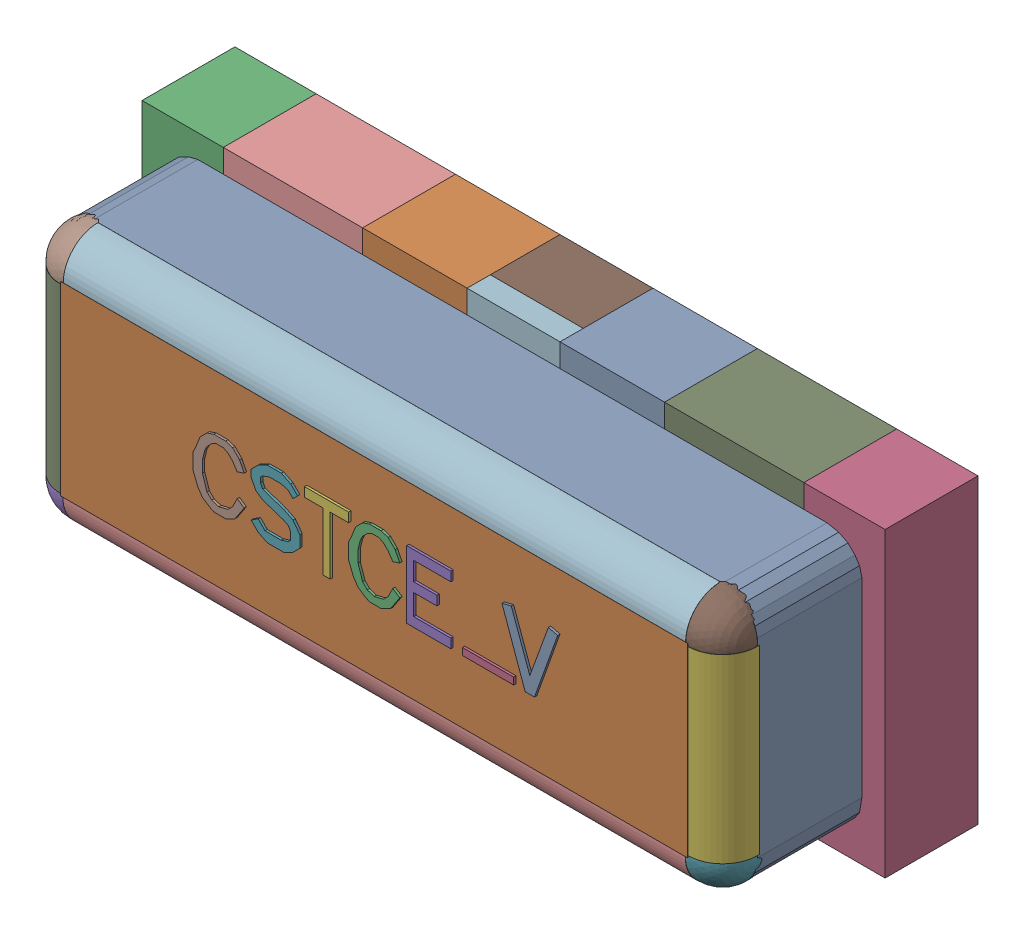
SolidWorks assembly User Library-Arduino Nano 3.0_User Library-CSTCE_V-1_Free-Models1, configuration Default. Lengths in mm.
Overall size (3.2 1.3 1.01).
50 component instances, 16 part files, 0 mates.
Components (placement in the parent):
- User Library-Arduino Nano 3.0_User Library-CSTCE_V-1_453563857-1: User Library-Arduino Nano 3.0_User Library-CSTCE_V-1_453563857 [Default] at (1.63 0.025 1.0127) size (0.24 0.29 0.01)
  - User Library-Arduino Nano 3.0_User Library-CSTCE_V-1_Extruded20-1: User Library-Arduino Nano 3.0_User Library-CSTCE_V-1_Extruded20 [Default] at origin size (0.24 0.29 0.01)
- User Library-Arduino Nano 3.0_User Library-CSTCE_V-1_453557585-1: User Library-Arduino Nano 3.0_User Library-CSTCE_V-1_453557585 [Default] at (0.95 0 0.8627) size (2.7 0.8 0.15)
  - User Library-Arduino Nano 3.0_User Library-CSTCE_V-1_Extruded15-1: User Library-Arduino Nano 3.0_User Library-CSTCE_V-1_Extruded15 [Default] at origin size (2.7 0.8 0.15)
- User Library-Arduino Nano 3.0_User Library-CSTCE_V-1_453563985-1: User Library-Arduino Nano 3.0_User Library-CSTCE_V-1_453563985 [Default] at (0.96 0.025 1.0127) size (0.22 0.29 0.01)
  - User Library-Arduino Nano 3.0_User Library-CSTCE_V-1_Extruded14-1: User Library-Arduino Nano 3.0_User Library-CSTCE_V-1_Extruded14 [Default] at origin size (0.22 0.29 0.01)
- User Library-Arduino Nano 3.0_User Library-CSTCE_V-1_453563601-1: User Library-Arduino Nano 3.0_User Library-CSTCE_V-1_453563601 [Default] at (1.45 -0.105 1.0127) size (0.22 0.03 0.01)
  - User Library-Arduino Nano 3.0_User Library-CSTCE_V-1_Extruded17-1: User Library-Arduino Nano 3.0_User Library-CSTCE_V-1_Extruded17 [Default] at origin size (0.22 0.03 0.01)
- User Library-Arduino Nano 3.0_User Library-CSTCE_V-1_453565905-1: User Library-Arduino Nano 3.0_User Library-CSTCE_V-1_453565905 [Default] at (1.195 0.025 1.0127) size (0.19 0.29 0.01)
  - User Library-Arduino Nano 3.0_User Library-CSTCE_V-1_Extruded21-1: User Library-Arduino Nano 3.0_User Library-CSTCE_V-1_Extruded21 [Default] at origin size (0.19 0.29 0.01)
- User Library-Arduino Nano 3.0_User Library-CSTCE_V-1_453566801-1: User Library-Arduino Nano 3.0_User Library-CSTCE_V-1_453566801 [Default] at (0.755 0.025 1.0127) size (0.19 0.29 0.01)
  - User Library-Arduino Nano 3.0_User Library-CSTCE_V-1_Extruded25-1: User Library-Arduino Nano 3.0_User Library-CSTCE_V-1_Extruded25 [Default] at origin size (0.19 0.29 0.01)
- User Library-Arduino Nano 3.0_User Library-CSTCE_V-1_453567057-1: User Library-Arduino Nano 3.0_User Library-CSTCE_V-1_453567057 [Default] at (0.535 0.025 1.0127) size (0.21 0.29 0.01)
  - User Library-Arduino Nano 3.0_User Library-CSTCE_V-1_Extruded23-1: User Library-Arduino Nano 3.0_User Library-CSTCE_V-1_Extruded23 [Default] at origin size (0.21 0.29 0.01)
- User Library-Arduino Nano 3.0_User Library-CSTCE_V-1_453563985-2: User Library-Arduino Nano 3.0_User Library-CSTCE_V-1_453563985 [Default] at (0.29 0.025 1.0127) size (0.22 0.29 0.01)
  - User Library-Arduino Nano 3.0_User Library-CSTCE_V-1_Extruded14-1: User Library-Arduino Nano 3.0_User Library-CSTCE_V-1_Extruded14 [Default] at origin size (0.22 0.29 0.01)
- User Library-Arduino Nano 3.0_User Library-CSTCE_V-1_453562833-1: User Library-Arduino Nano 3.0_User Library-CSTCE_V-1_453562833 [Default] at (1.9 0 0.0127) size (0.6 1.3 0.4)
  - User Library-Arduino Nano 3.0_User Library-CSTCE_V-1_Extruded18-1: User Library-Arduino Nano 3.0_User Library-CSTCE_V-1_Extruded18 [Default] at origin size (0.6 1.3 0.4)
- User Library-Arduino Nano 3.0_User Library-CSTCE_V-1_453562833-2: User Library-Arduino Nano 3.0_User Library-CSTCE_V-1_453562833 [Default] at (0 0 0.0127) size (0.6 1.3 0.4)
  - User Library-Arduino Nano 3.0_User Library-CSTCE_V-1_Extruded18-1: User Library-Arduino Nano 3.0_User Library-CSTCE_V-1_Extruded18 [Default] at origin size (0.6 1.3 0.4)
- User Library-Arduino Nano 3.0_User Library-CSTCE_V-1_453562065-1: User Library-Arduino Nano 3.0_User Library-CSTCE_V-1_453562065 [Default] at (0.95 0 0.0127) size (0.4 1.3 0.3)
  - User Library-Arduino Nano 3.0_User Library-CSTCE_V-1_Extruded16-1: User Library-Arduino Nano 3.0_User Library-CSTCE_V-1_Extruded16 [Default] at origin size (0.4 1.3 0.3)
- User Library-Arduino Nano 3.0_User Library-CSTCE_V-1_453566289-1: User Library-Arduino Nano 3.0_User Library-CSTCE_V-1_453566289 [Default] at (0.95 0 0.3127) size (0.4 1.3 0.1)
  - User Library-Arduino Nano 3.0_User Library-CSTCE_V-1_Extruded13-1: User Library-Arduino Nano 3.0_User Library-CSTCE_V-1_Extruded13 [Default] at origin size (0.4 1.3 0.1)
- User Library-Arduino Nano 3.0_User Library-CSTCE_V-1_453565777-1: User Library-Arduino Nano 3.0_User Library-CSTCE_V-1_453565777 [Default] at (1.375 0 0.0127) size (0.45 1.3 0.4)
  - User Library-Arduino Nano 3.0_User Library-CSTCE_V-1_Extruded24-1: User Library-Arduino Nano 3.0_User Library-CSTCE_V-1_Extruded24 [Default] at origin size (0.45 1.3 0.4)
- User Library-Arduino Nano 3.0_User Library-CSTCE_V-1_453565777-2: User Library-Arduino Nano 3.0_User Library-CSTCE_V-1_453565777 [Default] at (0.525 0 0.0127) size (0.45 1.3 0.4)
  - User Library-Arduino Nano 3.0_User Library-CSTCE_V-1_Extruded24-1: User Library-Arduino Nano 3.0_User Library-CSTCE_V-1_Extruded24 [Default] at origin size (0.45 1.3 0.4)
- User Library-Arduino Nano 3.0_User Library-CSTCE_V-1_453563729-1: User Library-Arduino Nano 3.0_User Library-CSTCE_V-1_453563729 [Default] at (-0.475 0 0.0127) size (0.35 1.3 0.4)
  - User Library-Arduino Nano 3.0_User Library-CSTCE_V-1_Extruded22-1: User Library-Arduino Nano 3.0_User Library-CSTCE_V-1_Extruded22 [Default] at origin size (0.35 1.3 0.4)
- User Library-Arduino Nano 3.0_User Library-CSTCE_V-1_453563729-2: User Library-Arduino Nano 3.0_User Library-CSTCE_V-1_453563729 [Default] at (2.375 0 0.0127) size (0.35 1.3 0.4)
  - User Library-Arduino Nano 3.0_User Library-CSTCE_V-1_Extruded22-1: User Library-Arduino Nano 3.0_User Library-CSTCE_V-1_Extruded22 [Default] at origin size (0.35 1.3 0.4)
- User Library-Arduino Nano 3.0_User Library-CSTCE_V-1_453330369-1: User Library-Arduino Nano 3.0_User Library-CSTCE_V-1_453330369 [Default] at (-0.4016 -0.4006 0.8627) size (0.3 0.3 0.3)
  - User Library-Arduino Nano 3.0_User Library-CSTCE_V-1_Sphere1-1: User Library-Arduino Nano 3.0_User Library-CSTCE_V-1_Sphere1 [Default] at origin size (0.3 0.3 0.3)
- User Library-Arduino Nano 3.0_User Library-CSTCE_V-1_453331489-1: User Library-Arduino Nano 3.0_User Library-CSTCE_V-1_453331489 [Default] at (2.3004 0.3894 0.8627) x (1 0 0) z (0 -1 0) size (0.3 0.3 0.78)
  - User Library-Arduino Nano 3.0_User Library-CSTCE_V-1_Cylinder3-1: User Library-Arduino Nano 3.0_User Library-CSTCE_V-1_Cylinder3 [Default] at origin size (0.3 0.3 0.78)
- User Library-Arduino Nano 3.0_User Library-CSTCE_V-1_453330369-2: User Library-Arduino Nano 3.0_User Library-CSTCE_V-1_453330369 [Default] at (2.3 -0.4006 0.8627) size (0.3 0.3 0.3)
  - User Library-Arduino Nano 3.0_User Library-CSTCE_V-1_Sphere1-1: User Library-Arduino Nano 3.0_User Library-CSTCE_V-1_Sphere1 [Default] at origin size (0.3 0.3 0.3)
- User Library-Arduino Nano 3.0_User Library-CSTCE_V-1_453330369-3: User Library-Arduino Nano 3.0_User Library-CSTCE_V-1_453330369 [Default] at (-0.4016 0.4006 0.8627) size (0.3 0.3 0.3)
  - User Library-Arduino Nano 3.0_User Library-CSTCE_V-1_Sphere1-1: User Library-Arduino Nano 3.0_User Library-CSTCE_V-1_Sphere1 [Default] at origin size (0.3 0.3 0.3)
- User Library-Arduino Nano 3.0_User Library-CSTCE_V-1_453331489-2: User Library-Arduino Nano 3.0_User Library-CSTCE_V-1_453331489 [Default] at (-0.4016 0.3894 0.8627) x (1 0 0) z (0 -1 0) size (0.3 0.3 0.78)
  - User Library-Arduino Nano 3.0_User Library-CSTCE_V-1_Cylinder3-1: User Library-Arduino Nano 3.0_User Library-CSTCE_V-1_Cylinder3 [Default] at origin size (0.3 0.3 0.78)
- User Library-Arduino Nano 3.0_User Library-CSTCE_V-1_453331041-1: User Library-Arduino Nano 3.0_User Library-CSTCE_V-1_453331041 [Default] at (-0.3908 -0.4013 0.8627) x (0 1 0) z (1 0 0) size (0.3 0.3 2.68)
  - User Library-Arduino Nano 3.0_User Library-CSTCE_V-1_Cylinder2-1: User Library-Arduino Nano 3.0_User Library-CSTCE_V-1_Cylinder2 [Default] at origin size (0.3 0.3 2.68)
- User Library-Arduino Nano 3.0_User Library-CSTCE_V-1_453330369-4: User Library-Arduino Nano 3.0_User Library-CSTCE_V-1_453330369 [Default] at (2.3 0.4006 0.8627) size (0.3 0.3 0.3)
  - User Library-Arduino Nano 3.0_User Library-CSTCE_V-1_Sphere1-1: User Library-Arduino Nano 3.0_User Library-CSTCE_V-1_Sphere1 [Default] at origin size (0.3 0.3 0.3)
- User Library-Arduino Nano 3.0_User Library-CSTCE_V-1_453331041-2: User Library-Arduino Nano 3.0_User Library-CSTCE_V-1_453331041 [Default] at (-0.3892 0.4001 0.8627) x (0 1 0) z (1 0 0) size (0.3 0.3 2.68)
  - User Library-Arduino Nano 3.0_User Library-CSTCE_V-1_Cylinder2-1: User Library-Arduino Nano 3.0_User Library-CSTCE_V-1_Cylinder2 [Default] at origin size (0.3 0.3 2.68)
- User Library-Arduino Nano 3.0_User Library-CSTCE_V-1_453565521-1: User Library-Arduino Nano 3.0_User Library-CSTCE_V-1_453565521 [Default] at (0.95 0 0.4127) size (3 1.1 0.45)
  - User Library-Arduino Nano 3.0_User Library-CSTCE_V-1_Extruded19-1: User Library-Arduino Nano 3.0_User Library-CSTCE_V-1_Extruded19 [Default] at origin size (3 1.1 0.45)
